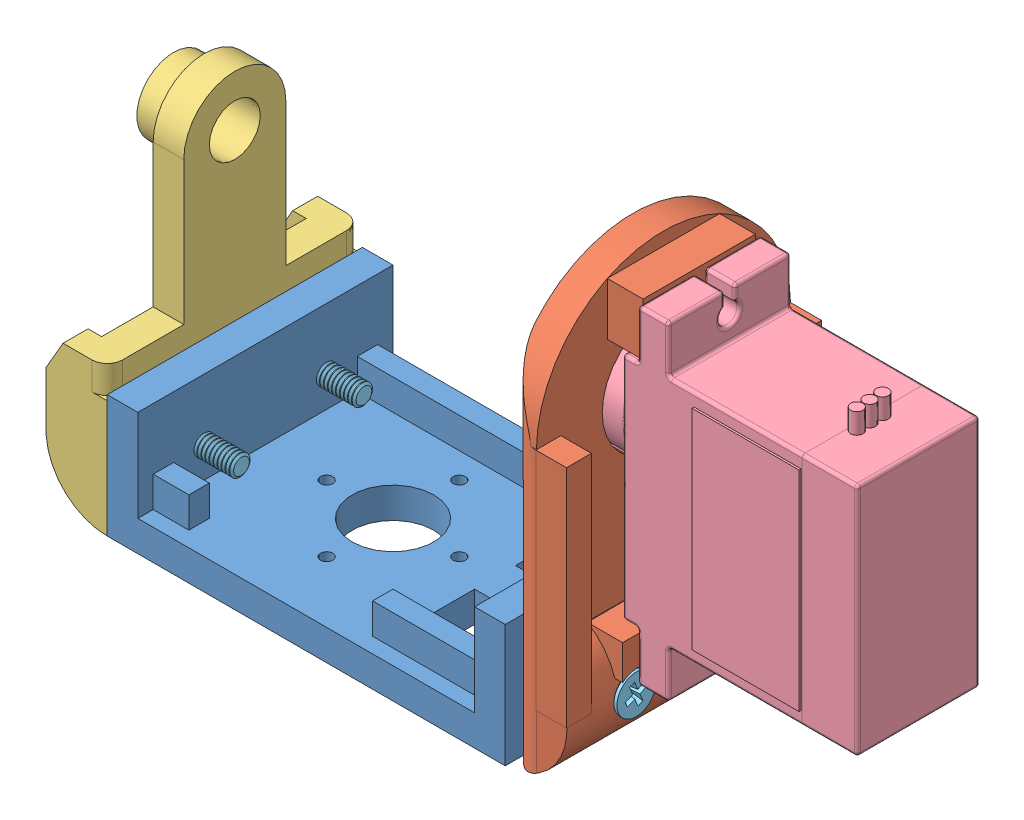
SolidWorks assembly Ensamblaje-Eslabon4, configuration Predeterminado. Lengths in mm.
Overall size (73.34 40.81 25.26).
8 component instances, 5 part files, 15 mates.
Components (placement in the parent):
- Eslabon4A-1: Eslabon4A [Predeterminado] at origin size (39 12 25)
- Eslabon4B-1: Eslabon4B [Predeterminado] at (20.4076 20.8175 -1.3719) x (0 1 0) z (0 0 -1) size (40.81 7.41 25.26)
- Eslabon4C-1: Eslabon4C [Predeterminado] at (-18.5924 16.8477 -0.8514) x (0 1 0) z (0 0 1) size (33.2 6 24.95)
- MG90S-Servo-1: MG90S-Servo [Default] at (48.4076 22.95 -1.248) x (0 1 0) z (0 0 1) size (32.2 32.5 12.4)
- flat head screw_am-1: flat head screw_am [B18.6.7M - M2 x 0.4 x 13 Type I Cross Recessed FHMS --13S] at (-24.9349 6 -7.248) x (1 0 0) z (0 0.526224 0.850346) size (13 3.8 3.8)
- flat head screw_am-2: flat head screw_am [B18.6.7M - M2 x 0.4 x 13 Type I Cross Recessed FHMS --13S] at (26.7489 6 -7.248) x (-1 0 0) z (0 0.689705 -0.724091) size (13 3.8 3.8)
- flat head screw_am-3: flat head screw_am [B18.6.7M - M2 x 0.4 x 13 Type I Cross Recessed FHMS --13S] at (26.7489 6 4.752) x (-1 0 0) z (0 -0.924225 -0.381849) size (13 3.8 3.8)
- flat head screw_am-4: flat head screw_am [B18.6.7M - M2 x 0.4 x 13 Type I Cross Recessed FHMS --13S] at (-24.9349 6 4.752) x (1 0 0) z (0 -0.35084 0.936436) size (13 3.8 3.8)
Mates (geometry in assembly coordinates):
- Coincidente1: coincident: plane of Eslabon4A-1 through (-18.5924 3 -13.748) normal (-1 0 0); plane of Eslabon4C-1 through (-18.5924 28.2 -1.248) normal (1 0 0)
- Concéntrica1: concentric: cylinder of Eslabon4A-1 through (26.4076 6 -7.248) axis (-1 0 0) radius 1; cylinder of Eslabon4C-1 through (-21.5924 6 -7.248) axis (1 0 0) radius 1
- Concéntrica2: concentric: cylinder of Eslabon4A-1 through (26.4076 6 4.752) axis (-1 0 0) radius 1; cylinder of Eslabon4C-1 through (-21.5924 6 4.752) axis (1 0 0) radius 1
- Coincidente2: coincident: plane of Eslabon4A-1 through (20.4076 3 -13.748) normal (1 0 0); plane of Eslabon4B-1 through (20.4076 28.1917 -1.2499) normal (-1 0 0)
- Concéntrica3: concentric: cylinder of Eslabon4A-1 through (26.4076 6 4.752) axis (-1 0 0) radius 1; cylinder of Eslabon4B-1 through (23.4076 6 4.752) axis (-1 0 0) radius 1
- Concéntrica4: concentric: cylinder of Eslabon4A-1 through (26.4076 6 -7.248) axis (-1 0 0) radius 1; cylinder of Eslabon4B-1 through (23.4076 6 -7.248) axis (-1 0 0) radius 1
- Concéntrica5: concentric: cylinder of Eslabon4B-1 through (23.4076 28.2 -1.248) axis (-1 0 0) radius 6; cylinder of MG90S-Servo-1 through (19.4076 28.2 -1.248) axis (1 0 0) radius 5.75
- Coincidente3: coincident: plane of Eslabon4B-1 through (26.9076 20.8175 -1.3719) normal (1 0 0); plane of MG90S-Servo-1 through (26.9076 22.95 -1.248) normal (-1 0 0)
- Paralelo1: parallel: plane of Eslabon4B-1 through (26.4076 28.3 8.802) normal (0 0 -1); plane of MG90S-Servo-1 through (29.9076 11.45 4.752) normal (0 0 1)
- Coincidente4: coincident: axis of Eslabon4B-1 through (27.2956 6 -7.248) axis (-1 0 0); axis of flat head screw_am-2 through (13.9071 6 -7.248) axis (-1 0 0)
- Coincidente5: coincident: axis of Eslabon4B-1 through (26.4076 6 4.752) axis (-1 0 0); axis of flat head screw_am-3 through (13.9071 6 4.752) axis (-1 0 0)
- Coincidente6: coincident: axis of Eslabon4C-1 through (-24.5924 6 4.752) axis (1 0 0); axis of flat head screw_am-4 through (-12.1698 6 4.752) axis (-1 0 0)
- Coincidente7: coincident: axis of Eslabon4C-1 through (-24.5924 6 -7.248) axis (1 0 0); axis of flat head screw_am-1 through (-12.0932 6 -7.248) axis (1 0 0)
- Coincidente8: coincident: plane of flat head screw_am-1 through (-24.9349 6 -7.248) normal (-1 0 0); circle of flat head screw_am-4
- Coincidente9: coincident: plane of flat head screw_am-2 through (26.7489 6 -7.248) normal (1 0 0); plane of flat head screw_am-3 through (26.7489 6 4.752) normal (1 0 0)
